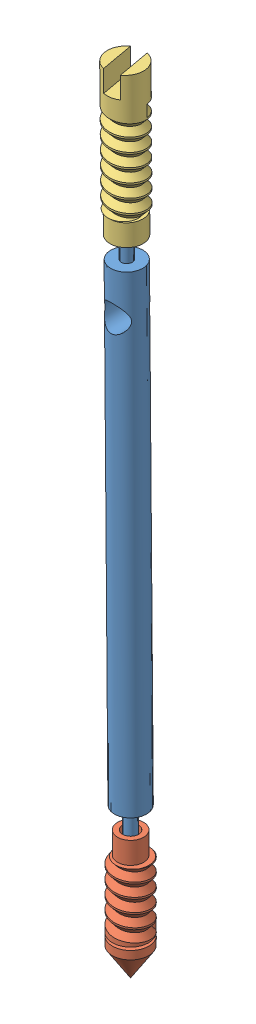
SolidWorks assembly Middle Rod, configuration Default. Lengths in mm.
Overall size (6.84 117.5 6.59).
3 component instances, 3 part files, 6 mates.
Components (placement in the parent):
- SHW 5 Rod-1: SHW 5 Rod [Default] at (2.5001 41.0047 2.3813) x (0 0 1) z (-0.999967 -0.008122 0) size (4.76 82.55 4.76)
- SHW 5 BotScrew-2: SHW 5 BotScrew [Default] at (2.4915 18.7795 2.3813) x (1 -0.000391 0) z (0 0 1) size (5.67 19.05 5.53)
- SHW 5 TopScrew-1: SHW 5 TopScrew [Default] at (1.907 114.0273 2.3813) x (0.983879 0.007992 -0.178659) z (0.008122 -0.999967 0) size (5.53 5.69 22.23)
Mates (geometry in assembly coordinates):
- Coincident1: coincident: point of SHW 5 Rod-1; point of SHW 5 TopScrew-1
- Concentric6: concentric aligned: cylinder of SHW 5 Rod-1 through (1.8565 120.246 2.3813) axis (-0.008122 0.999967 0) radius 0.8128; cylinder of SHW 5 TopScrew-1 through (1.7265 136.2515 2.3813) axis (-0.008122 0.999967 0) radius 1.3675
- Concentric9: concentric anti-aligned: cone of SHW 5 Rod-1 through (2.4982 36.1632 2.3813) axis (0.000391 1 0); cylinder of SHW 5 BotScrew-2 through (2.4915 18.7795 2.3813) axis (-0.000391 -1 0) radius 1.1906
- Coincident5: coincident: point of SHW 5 Rod-1; point of SHW 5 BotScrew-2
- Tangent1: tangent anti-aligned: cylinder of SHW 5 Rod-1 through (1.9328 110.8524 2.3813) axis (0.008122 -0.999967 0) radius 2.3813; plane of assembly through (0 0 0) normal (0 0 1)
- Tangent3: tangent anti-aligned: cylinder of SHW 5 Rod-1 through (1.9844 104.5026 0) axis (0 0 1) radius 1.9844; plane of assembly through (0 0 0) normal (1 0 0)
